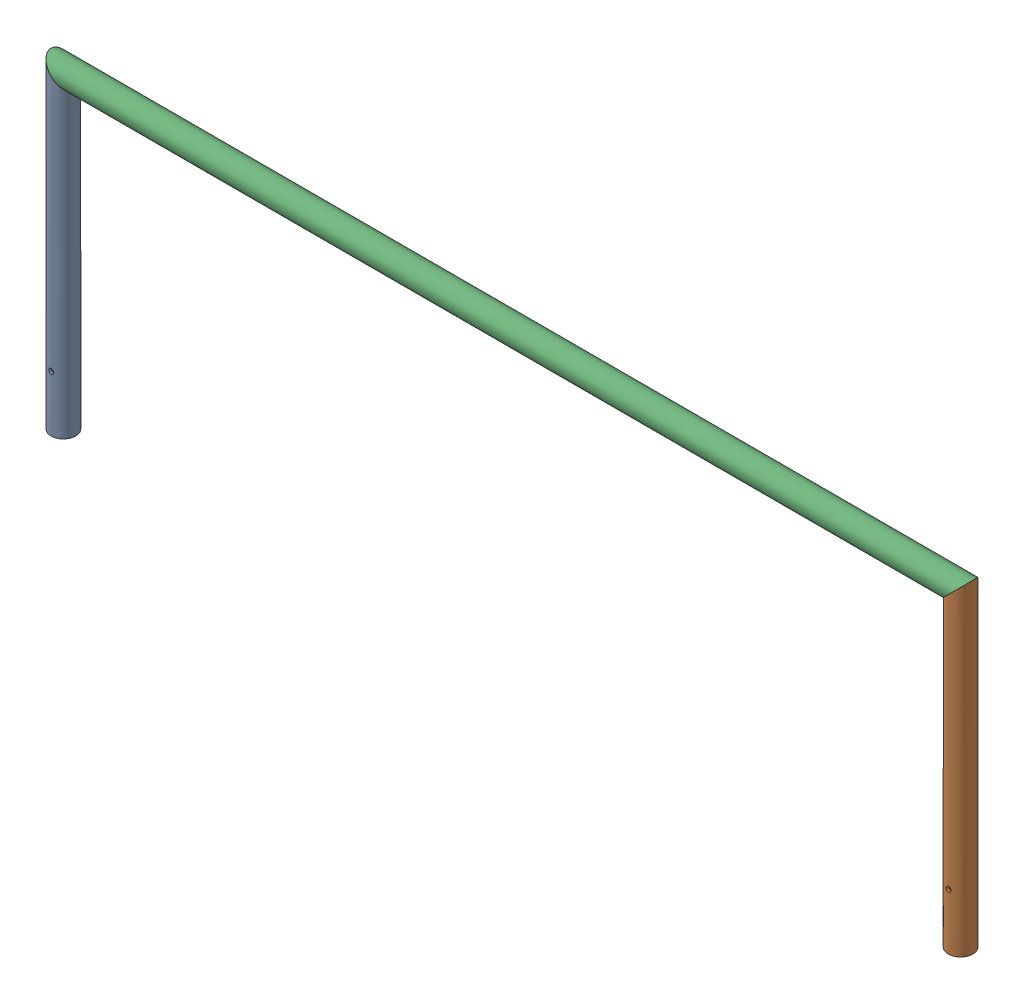
SolidWorks assembly GE-16030_ASM, configuration Default. Lengths in mm.
Overall size (1252.6 439.8 33.4).
3 component instances, 2 part files, 0 mates.
Components (placement in the parent):
- GE-16030-01-1: GE-16030-01 [Default] at origin size (33.4 439.8 33.4)
- GE-16030-01-2: GE-16030-01 [Default] at (1219.2 0 0) x (-1 0 0) z (0 0 -1) size (33.4 439.8 33.4)
- GE-16030-02-1: GE-16030-02 [Default] at (-16.7005 423.1005 0) size (1252.6 33.4 33.4)
